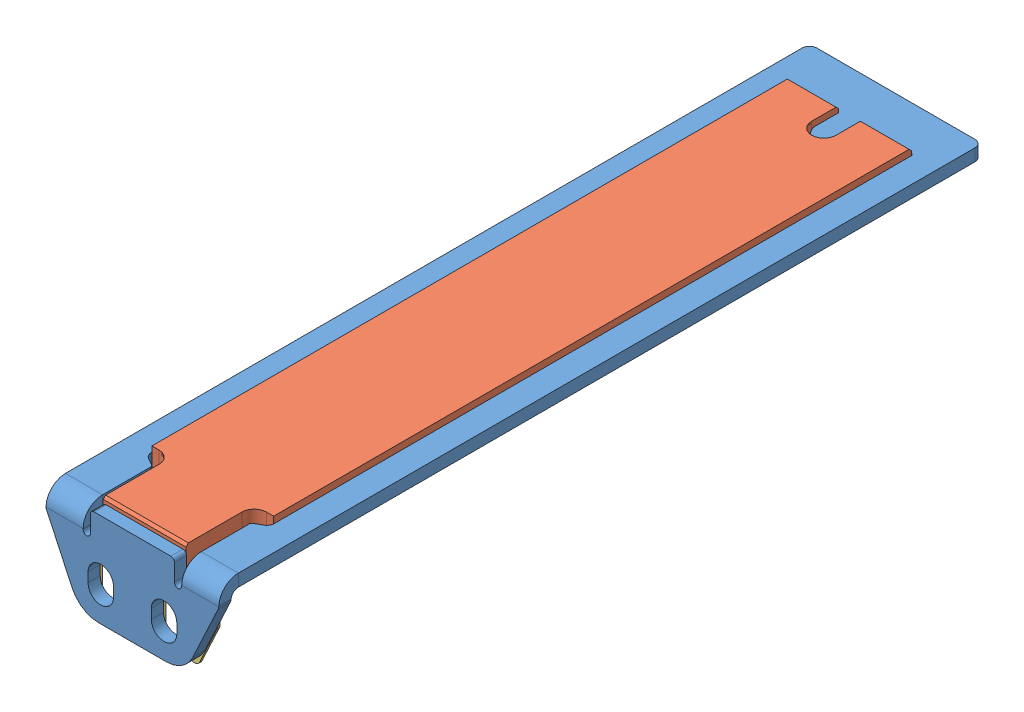
SolidWorks assembly glid_7_op, configuration Default. Lengths in mm.
Overall size (71.01 40.85 313.61).
3 component instances, 3 part files, 9 mates.
Components (placement in the parent):
- 6300368-1: 6300368 [Default] at (-35.5 0 -308.5979) x (0 0 -1) z (0 -1 0) size (313.61 71.01 38.5)
- 63669-1: 63669 [6381474] at (25 -1.5 0) x (0 0 -1) z (0 1 0) size (290 50 9)
- 6300568-1: 6300568 [Default] at (0 -1.5 -1.3846) x (0 0 1) z (0 -1 0) size (291.38 60 31.38)
Mates (geometry in assembly coordinates):
- Coincident1: coincident anti-aligned: plane of 6300368-1 through (-13.8659 -21.3479 0) normal (0 0 -1); plane of assembly through (0 0 0) normal (0 0 1)
- Coincident2: coincident anti-aligned: plane of 6300368-1 through (-13.8659 0 22.6521) normal (0 -1 0); plane of assembly through (0 0 0) normal (0 1 0)
- Coincident3: coincident: line of 6300368-1 through (0 5 -280.5979) axis (0 -1 0); plane of assembly through (0 0 0) normal (1 0 0)
- Coincident4: coincident anti-aligned: plane of 6300368-1 through (-13.8659 0 22.6521) normal (0 -1 0); plane of 63669-1 through (22 0 -2) normal (0 1 0)
- Coincident5: coincident anti-aligned: plane of 6300368-1 through (-13.8659 -21.3479 0) normal (0 0 -1); plane of 63669-1 through (17 7.5 0) normal (0 0 1)
- Symmetric5: symmetric aligned: plane of 63669-1 through (25 7.5 -7) normal (1 0 0); plane of 63669-1 through (-25 7.5 -290) normal (-1 0 0); plane of assembly through (0 0 0) normal (1 0 0)
- Coincident6: coincident anti-aligned: plane of 63669-1 through (22 -1.5 -2) normal (0 -1 0); plane of 6300568-1 through (-13 -1.5 12.6154) normal (0 1 0)
- Coincident7: coincident anti-aligned: plane of 6300368-1 through (-13.8659 -21.3479 0) normal (0 0 -1); plane of 6300568-1 through (-13 -16.8846 0) normal (0 0 1)
- Symmetric6: symmetric aligned: plane of 6300368-1 through (35.5 5 -305.5979) normal (1 0 0); plane of 6300568-1 through (-35.5 5 -305.5979) normal (-1 0 0); plane of 6300368-1 through (0 -1.5 -1.3846) normal (-1 0 0)
